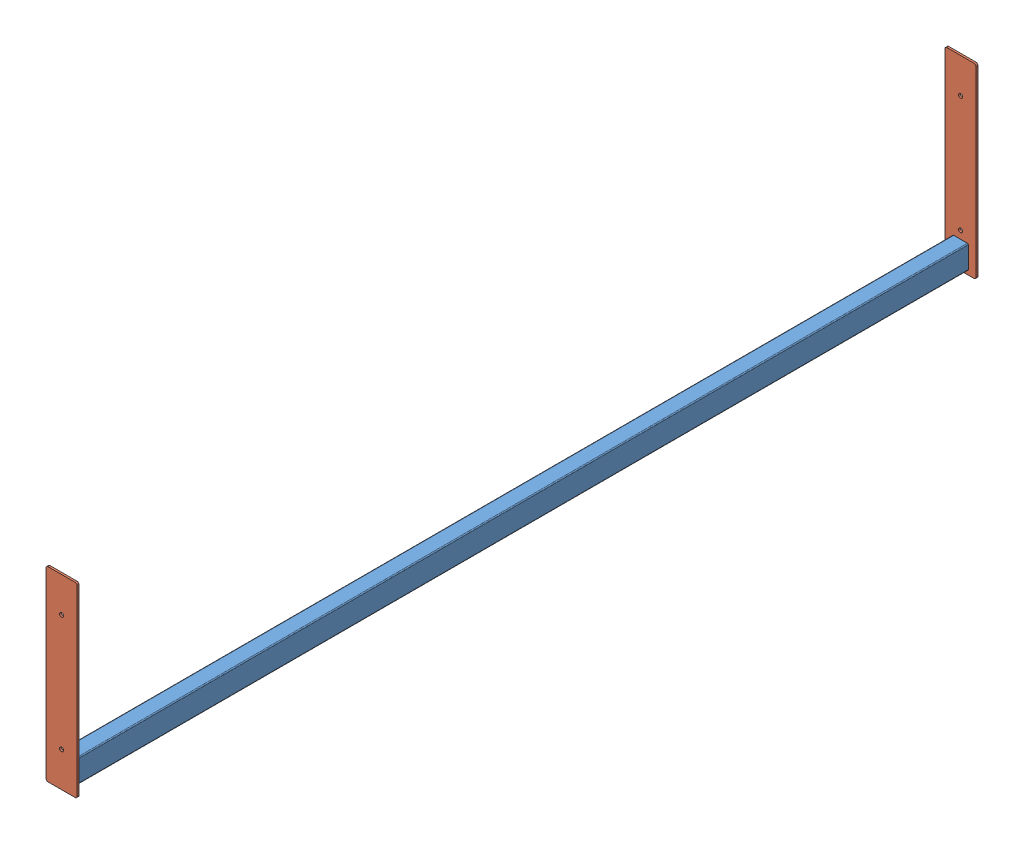
SolidWorks assembly cross bar assy, configuration Default. Lengths in mm.
Overall size (101.6 609.6 2946.4).
3 component instances, 2 part files, 6 mates.
Components (placement in the parent):
- cross bar-1: cross bar [Default] at origin size (50.8 76.2 2933.7)
- tube mount-1: tube mount [Default] at (0 254 1466.85) size (101.6 609.6 6.35)
- tube mount-2: tube mount [Default] at (0 254 -1473.2) size (101.6 609.6 6.35)
Mates (geometry in assembly coordinates):
- Coincident1: coincident aligned: plane of tube mount-1 through (0 254 1466.85) normal (1 0 0); plane of assembly
- Coincident2: coincident aligned: plane of tube mount-2 through (0 254 -1473.2) normal (1 0 0); plane of assembly
- Coincident3: coincident anti-aligned: plane of cross bar-1 through (-22.225 -34.925 1466.85) normal (0 0 1); plane of tube mount-1 through (-44.45 552.45 1466.85) normal (0 0 -1)
- Distance1: distance = 12.7 mm aligned: plane of tube mount-1 through (-44.45 -50.8 1473.2) normal (0 -1 0); plane of cross bar-1 through (-22.225 -38.1 1466.85) normal (0 -1 0)
- Coincident5: coincident anti-aligned: plane of cross bar-1 through (-22.225 -34.925 -1466.85) normal (0 0 -1); plane of tube mount-2 through (-44.45 552.45 -1466.85) normal (0 0 1)
- Distance2: distance = 12.7 mm aligned: plane of cross bar-1 through (-22.225 -38.1 1466.85) normal (0 -1 0); plane of tube mount-2 through (-44.45 -50.8 -1466.85) normal (0 -1 0)
